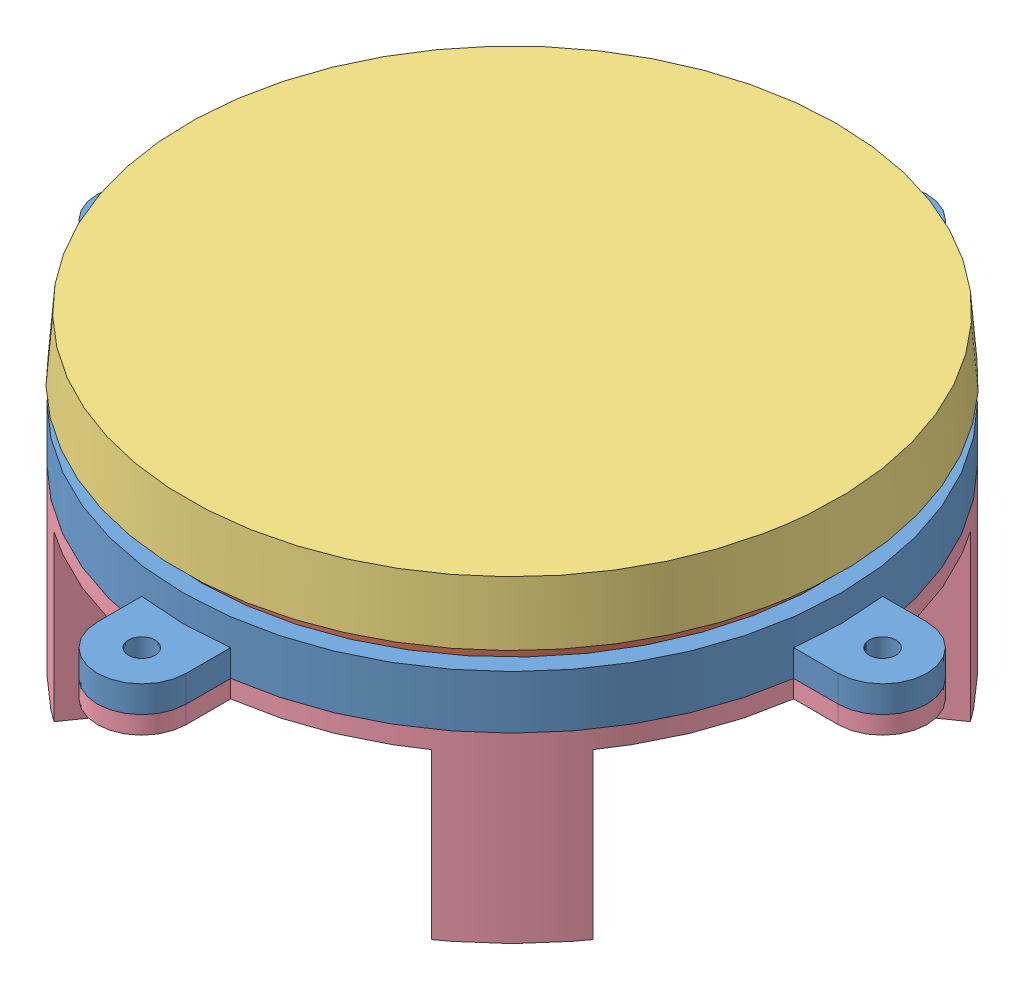
SolidWorks assembly Pitri_Dish_Stand, configuration Default. Lengths in mm.
Overall size (118.52 44.98 118.52).
5 component instances, 4 part files, 6 mates.
Components (placement in the parent):
- Pitri_Dish_Holder-1: Pitri_Dish_Holder [Default] at (67.4847 69.8419 73.2764) size (118.52 7.62 118.52)
- Pitri Dish-1: Pitri Dish [Default] at (21.0975 36.3873 4.6108) x (0.999936 0 0.011288) z (-0.011288 0 0.999936) size (105.98 15.9 105.98)
  - Pitri Dish Bottom-1: Pitri Dish Bottom [Default] at (47.1593 37.2646 68.1376) size (89.71 14.88 89.71)
  - Pitri Dish Top-1: Pitri Dish Top [Default] at (47.1593 52.403 68.1376) x (0.134295 0 -0.990941) z (-0.990941 0 -0.134295) size (94.18 8.66 94.18)
- Part5^Pitri_Dish_Stand-1: Part5^Pitri_Dish_Stand [Default] at (67.4847 69.8419 73.2764) x (-1 0 0) z (0 -1 0) size (118.52 118.52 26.04) (virtual)
Mates (geometry in assembly coordinates):
- Concentric1: concentric aligned: cylinder of Pitri_Dish_Holder-1 through (67.4847 77.4619 73.2764) axis (0 -1 0) radius 44.45; cone of Pitri Dish-1/Pitri Dish Bottom-1 through (67.4847 73.6519 73.2764) axis (0 -1 0)
- Coincident1: coincident anti-aligned: plane of Pitri_Dish_Holder-1 through (67.4847 73.6519 73.2764) normal (0 1 0); plane of Pitri Dish-1/Pitri Dish Bottom-1 through (67.4847 73.6519 73.2764) normal (0 -1 0)
- InPlace1: in place: plane of Pitri_Dish_Holder-1 through (67.4847 69.8419 73.2764) normal (0 -1 0); plane of ? through (0 69.8419 0) normal (0 -1 0); moOrthogonalPlaneRef_w of Pitri_Dish_Holder-1 through (67.4847 69.8419 73.2764) normal (0 -1 0); unknown of ?; plane of Pitri_Dish_Holder-1 through (67.4847 69.8419 73.2764) normal (0 -1 0); line of ? through (-55 0 69.8419) axis (0 -1 0); plane of Pitri_Dish_Holder-1 through (67.4847 69.8419 73.2764) normal (0 -1 0); unknown of Part5^Pitri_Dish_Stand-1
- Coincident2: coincident aligned: plane of Pitri_Dish_Holder-1; plane of Part5^Pitri_Dish_Stand-1
- Coincident3: coincident aligned: moOrthogonalPlaneRef_w of Pitri_Dish_Holder-1 through (67.4847 69.8419 73.2764) normal (0 0 -1); plane of Part5^Pitri_Dish_Stand-1
- Coincident4: coincident anti-aligned: moOrthogonalPlaneRef_w of Pitri_Dish_Holder-1 through (67.4847 69.8419 73.2764) normal (1 0 0); plane of Part5^Pitri_Dish_Stand-1
